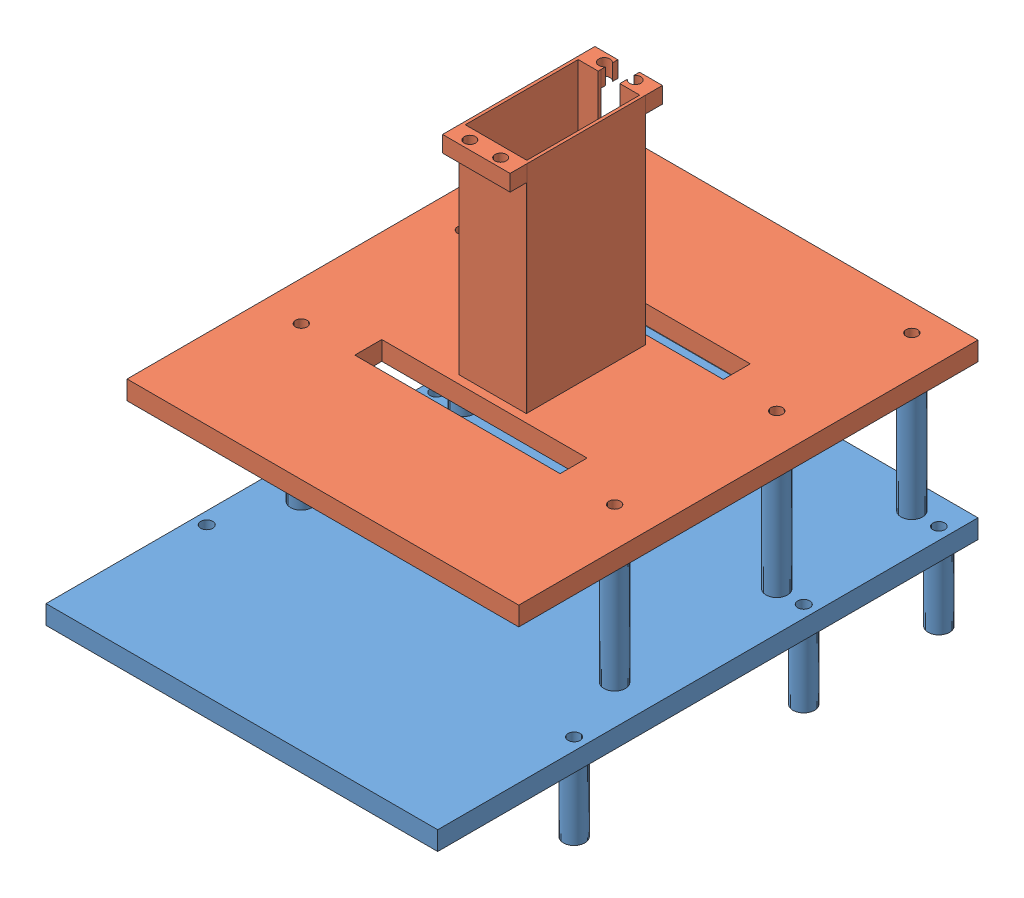
SolidWorks assembly Spirit40 Camera Mount, configuration Default. Lengths in mm.
Overall size (145 169 200).
2 component instances, 2 part files, 3 mates.
Components (placement in the parent):
- Payload Base-1: Payload Base [Default] at (63.5325 83.801 164.1893) x (1 0 0) z (0 0 -1) size (145 82 200)
- Payload Top-1: Payload Top [Default] at (63.5325 133.801 149.1893) size (145 87 170)
Mates (geometry in assembly coordinates):
- Concentric1: concentric aligned: cylinder of Payload Base-1 through (121.5325 51.801 184.1893) axis (0 1 0) radius 2.25; cylinder of Payload Top-1 through (121.5325 133.801 184.1893) axis (0 1 0) radius 2.15
- Coincident3: coincident anti-aligned: plane of Payload Base-1 through (121.5325 133.801 124.1893) normal (0 1 0); plane of Payload Top-1 through (63.5325 133.801 149.1893) normal (0 -1 0)
- Concentric8: concentric aligned: cylinder of Payload Base-1 through (5.5325 51.801 184.1893) axis (0 1 0) radius 2.25; cylinder of Payload Top-1 through (5.5325 133.801 184.1893) axis (0 1 0) radius 2.15
